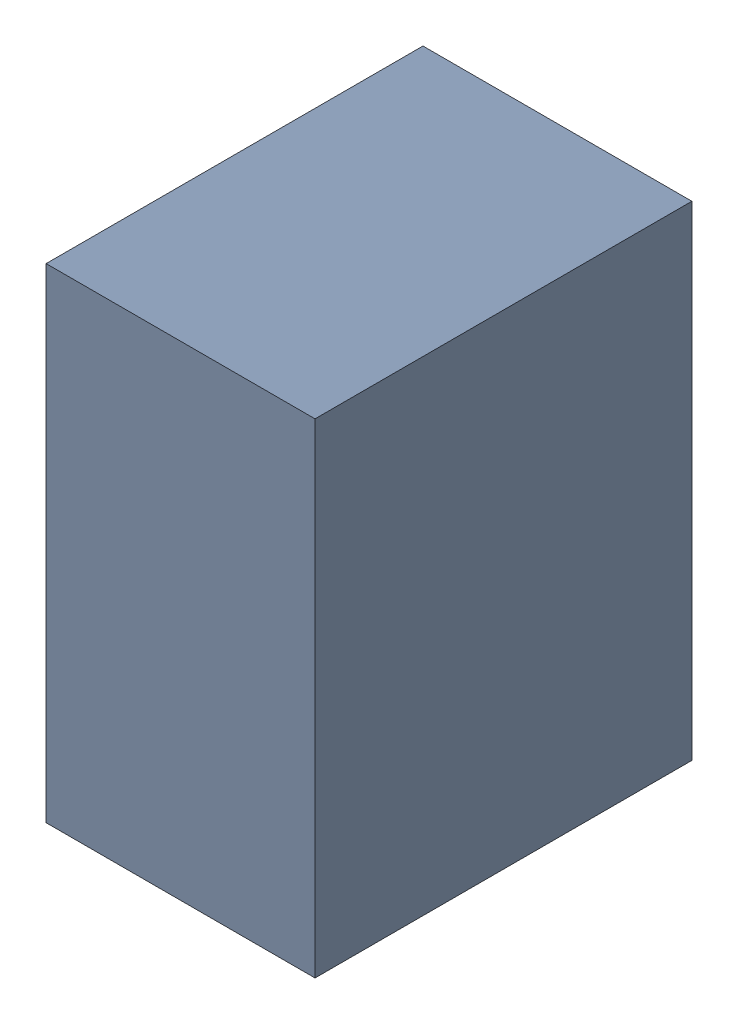
SolidWorks assembly C18, configuration Default. Lengths in mm.
Overall size (1 1.8 1.4).
3 component instances, 2 part files, 0 mates.
Components (placement in the parent):
- 1088883208-1: 1088883208 [Default] at (15 16.875 0) size (1 1.8 1.4)
  - Extruded-45-1: Extruded-45 [Default] at origin size (1 1.8 1.4)
- C0603-1: C0603 [Default] at (15.4001 16.0749 0) x (0 1 0) z (1 0 0) size (1.6 0.5 0.8)
